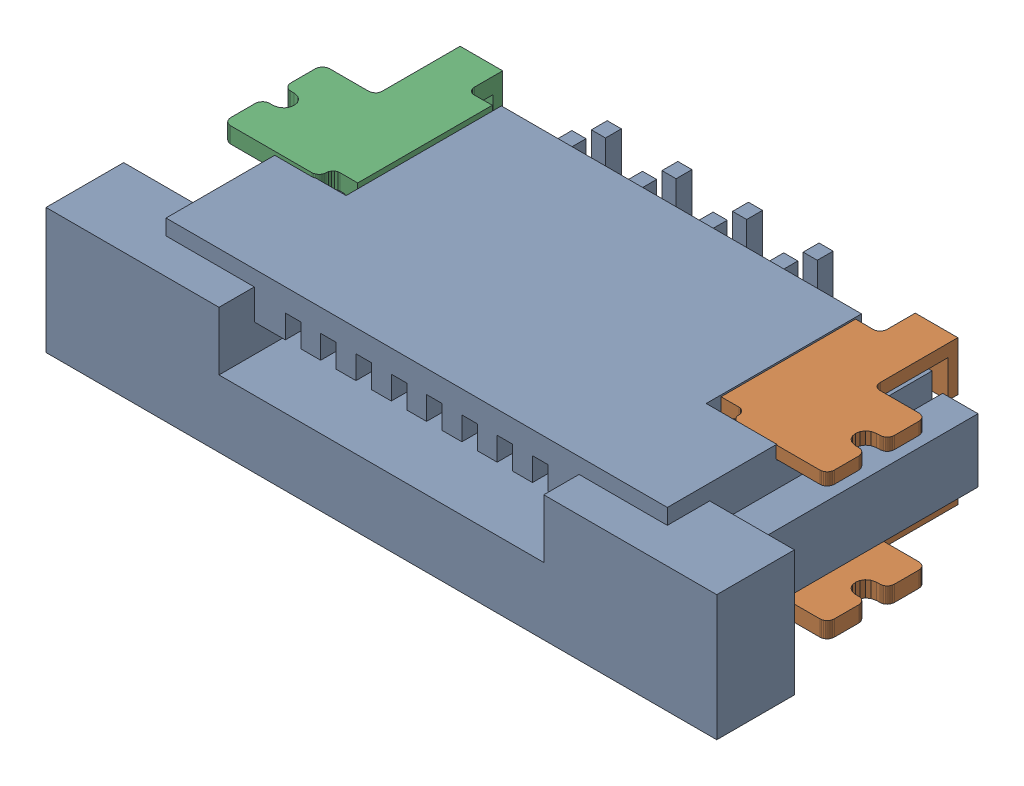
SolidWorks assembly P6主板_V1.0, configuration 默认. Lengths in mm.
Overall size (9.5 2.54 4.64).
4 component instances, 3 part files, 0 mates.
Components (placement in the parent):
- Header-FPC-ZIF-SMD-Vertical_Single-0.5-8-1: Header-FPC-ZIF-SMD-Vertical_Single-0.5-8 [默认] at (94.2958 47.7766 4.08) x (-1 0 0) z (0 0 1) size (9.5 2.54 4.64)
  - ffc_fpc_affc20-08-050-shb-t_01-1: ffc_fpc_affc20-08-050-shb-t_01 [默认] at origin size (9.5 2.54 4.55)
  - ffc_fpc_affc20-08-050-shb-t_02-1: ffc_fpc_affc20-08-050-shb-t_02 [默认] at origin size (1.7 2.05 2.6)
  - ffc_fpc_affc20-08-050-shb-t_03-1: ffc_fpc_affc20-08-050-shb-t_03 [默认] at origin size (1.7 2.05 2.6)
